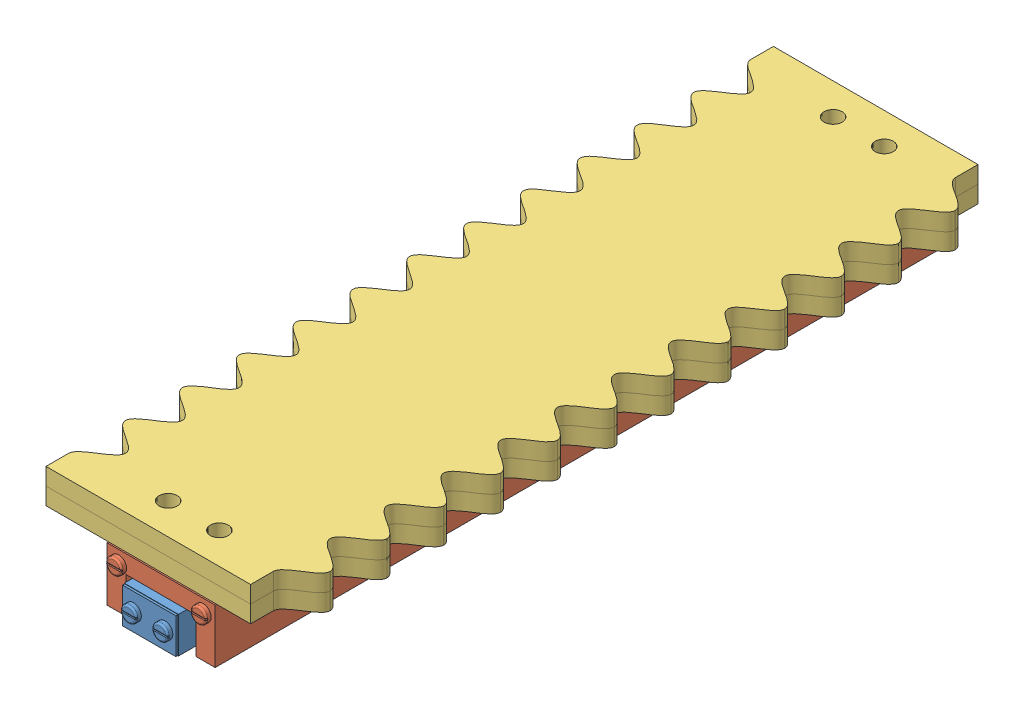
SolidWorks assembly linear_slide, configuration Default. Lengths in mm.
Overall size (41.42 16.41 131.35).
4 component instances, 3 part files, 11 mates.
Components (placement in the parent):
- EA-5BH-1: EA-5BH [Default] at origin size (9.53 6.35 130.39)
- EA-5CR-1: EA-5CR [Default] at (1.1141 0.889 -0.9629) size (19.05 9.53 130.39)
- rack-5: rack [Default] at (1.1141 10.414 63.2991) x (0 0 -1) z (1 0 0) size (128 3 41.42)
- rack-6: rack [Default] at (1.1141 13.414 63.2991) x (0 0 -1) z (1 0 0) size (128 3 41.42)
Mates (geometry in assembly coordinates):
- Concentric1: concentric aligned: cylinder of EA-5CR-1 through (-3.3859 10.414 121.7991) axis (0 1 0) radius 1.5; cylinder of ? through (-3.3859 10.414 121.7991) axis (0 1 0) radius 1.6
- Concentric2: concentric aligned: cylinder of EA-5CR-1 through (5.6141 10.414 121.7991) axis (0 1 0) radius 1.5; cylinder of ? through (5.6141 10.414 121.7991) axis (0 1 0) radius 1.6
- Concentric3: concentric aligned: cylinder of ? through (5.6141 10.414 121.7991) axis (0 1 0) radius 1.6; cylinder of ? through (5.6141 13.414 121.7991) axis (0 1 0) radius 1.6
- Concentric4: concentric aligned: cylinder of ? through (-3.3859 10.414 4.7991) axis (0 1 0) radius 1.6; cylinder of ? through (-3.3859 13.414 4.7991) axis (0 1 0) radius 1.6
- Coincident5: coincident anti-aligned: plane of ? through (1.1141 13.414 63.2991) normal (0 1 0); plane of ? through (1.1141 13.414 63.2991) normal (0 -1 0)
- Coincident6: coincident: plane of EA-5CR-1 through (10.6391 10.414 -0.9629) normal (0 1 0); plane of rack-5 through (1.1141 10.414 63.2991) normal (0 -1 0)
- Concentric5: concentric: cylinder of EA-5CR-1 through (-3.3859 10.414 121.7991) axis (0 1 0) radius 1.5; cylinder of rack-5 through (-3.3859 10.414 121.7991) axis (0 1 0) radius 1.6
- Concentric6: concentric aligned: cylinder of EA-5CR-1 through (5.6141 10.414 121.7991) axis (0 1 0) radius 1.5; cylinder of rack-5 through (5.6141 10.414 121.7991) axis (0 1 0) radius 1.6
- Coincident7: coincident: plane of rack-5 through (1.1141 13.414 63.2991) normal (0 1 0); plane of rack-6 through (1.1141 13.414 63.2991) normal (0 -1 0)
- Concentric7: concentric: cylinder of rack-5 through (5.6141 10.414 121.7991) axis (0 1 0) radius 1.6; cylinder of rack-6 through (5.6141 13.414 121.7991) axis (0 1 0) radius 1.6
- Concentric8: concentric aligned: cylinder of rack-5 through (-3.3859 10.414 121.7991) axis (0 1 0) radius 1.6; cylinder of rack-6 through (-3.3859 13.414 121.7991) axis (0 1 0) radius 1.6
